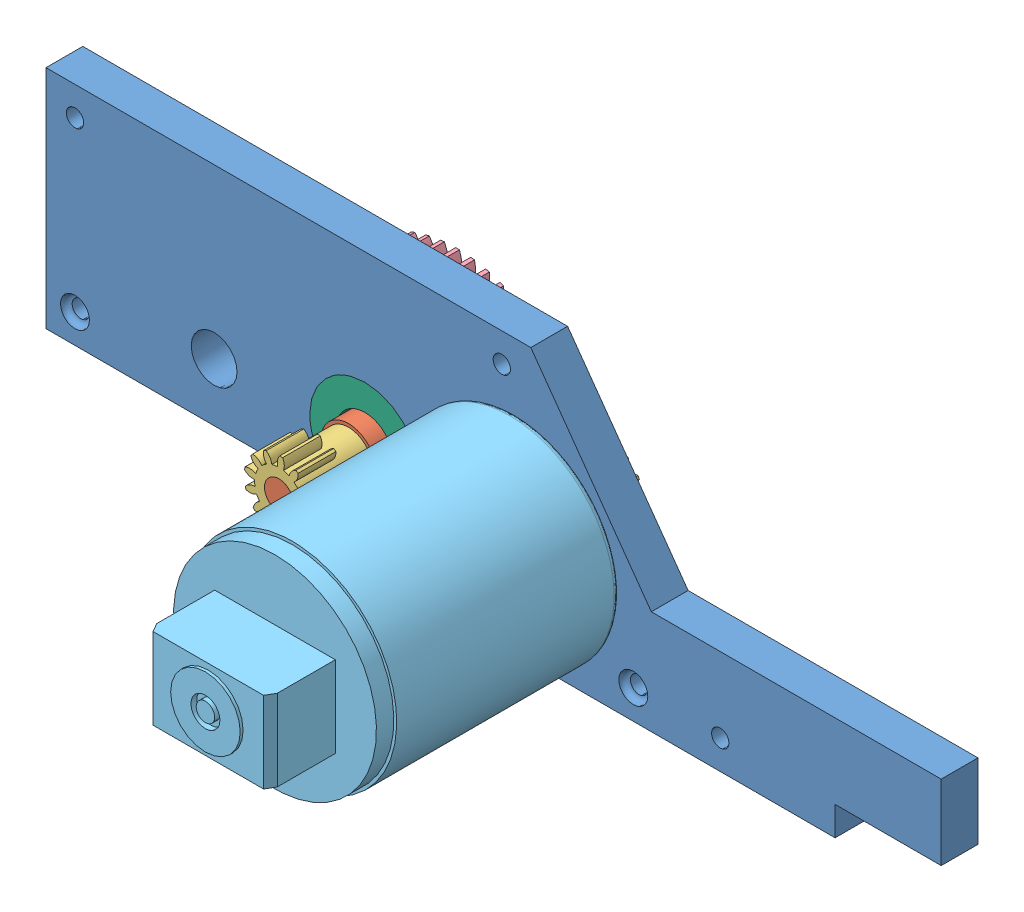
SolidWorks assembly MotorMountDerechoAlvaro, configuration Predeterminado. Lengths in mm.
Overall size (154.41 54 69.5).
9 component instances, 6 part files, 7 mates.
Components (placement in the parent):
- B_Motor_Derecha_Alvaro-1: B_Motor_Derecha_Alvaro [Predeterminado] at (43.0754 -12.0207 159.3322) x (-1 0 0) z (0 0 -1) size (154.41 47 6.35)
- CopleEngrane-1: CopleEngrane [Predeterminado] at (-61.2505 -9.4005 154.3995) x (0 0 -1) z (0.984779 0.173814 0) size (30.68 43.16 43.16)
  - Cople-1: Cople [Predeterminado] at (4.4173 -10.5202 49.0087) x (0 0 -1) z (0 -1 0) size (34.5 28.68 34.5)
  - Gear 13T-1: Gear 13T [Default] at (-13.2577 -10.5202 49.0087) x (-1 0 0) z (0 0 -1) size (12 11.88 11.96)
  - Gear_52T-1: Gear_52T [Predeterminado] at (4.4173 -10.5202 49.0087) size (6.5 43.16 43.16)
- MotorEngrane-1: MotorEngrane [Predeterminado] at (19.9901 -79.5422 177.3161) x (1 0 0) z (0 1 0) size (36 69.5 36)
  - Motor-1: Motor [Default] at (-5.1493 -20.5161 68.3) size (36 68.3 36)
  - Gear 13T-1: Gear 13T [Default] at (-5.1493 27.4839 68.3) x (0 1 0) z (-0.927124 0 -0.374755) size (12 11.88 11.96)
- valero-1: valero [Predeterminado] at (-11.1592 -11.2422 154.3322) x (0.98096 -0.194212 0) z (0 0 1) size (19 19 5)
Mates (geometry in assembly coordinates):
- Concéntrica3: concentric: cylinder of B_Motor_Derecha_Alvaro-1 through (-11.1592 -11.2422 154.3322) axis (0 0 1) radius 9.5; cylinder of valero-1 through (-11.1592 -11.2422 159.3322) axis (0 0 -1) radius 9.5
- Coincidente3: coincident: plane of B_Motor_Derecha_Alvaro-1 through (-11.1592 -11.2422 154.3322) normal (0 0 1); plane of valero-1 through (-11.1592 -11.2422 154.3322) normal (0 0 -1)
- Concéntrica4: concentric: cylinder of B_Motor_Derecha_Alvaro-1 through (-11.1592 -11.2422 152.9812) axis (0 0 1) radius 5; cylinder of CopleEngrane-1/Cople-1 through (-11.1592 -11.2422 162.1572) axis (0 0 -1) radius 4.75
- Coincidente4: coincident: plane of B_Motor_Derecha_Alvaro-1 through (43.0754 -12.0207 152.9822) normal (0 0 -1); plane of CopleEngrane-1/Cople-1 through (-11.1592 -11.2422 152.9822) normal (0 0 1)
- Concéntrica5: concentric: cylinder of B_Motor_Derecha_Alvaro-1 through (14.8408 -11.2422 152.9822) axis (0 0 1) radius 7.5; cylinder of MotorEngrane-1/Motor-1 through (14.8408 -11.2422 155.3322) axis (0 0 1) radius 5.1
- Paralelo1: parallel: plane of B_Motor_Derecha_Alvaro-1 through (-66.1592 17.7578 152.9822) normal (0 1 0); plane of MotorEngrane-1/Motor-1 through (-11.551 -4.2422 200.8322) normal (0 1 0)
- Coincidente6: coincident: plane of B_Motor_Derecha_Alvaro-1 through (43.0754 -12.0207 159.3322) normal (0 0 1); plane of MotorEngrane-1/Motor-1 through (14.8408 -11.2422 159.3322) normal (0 0 -1)
